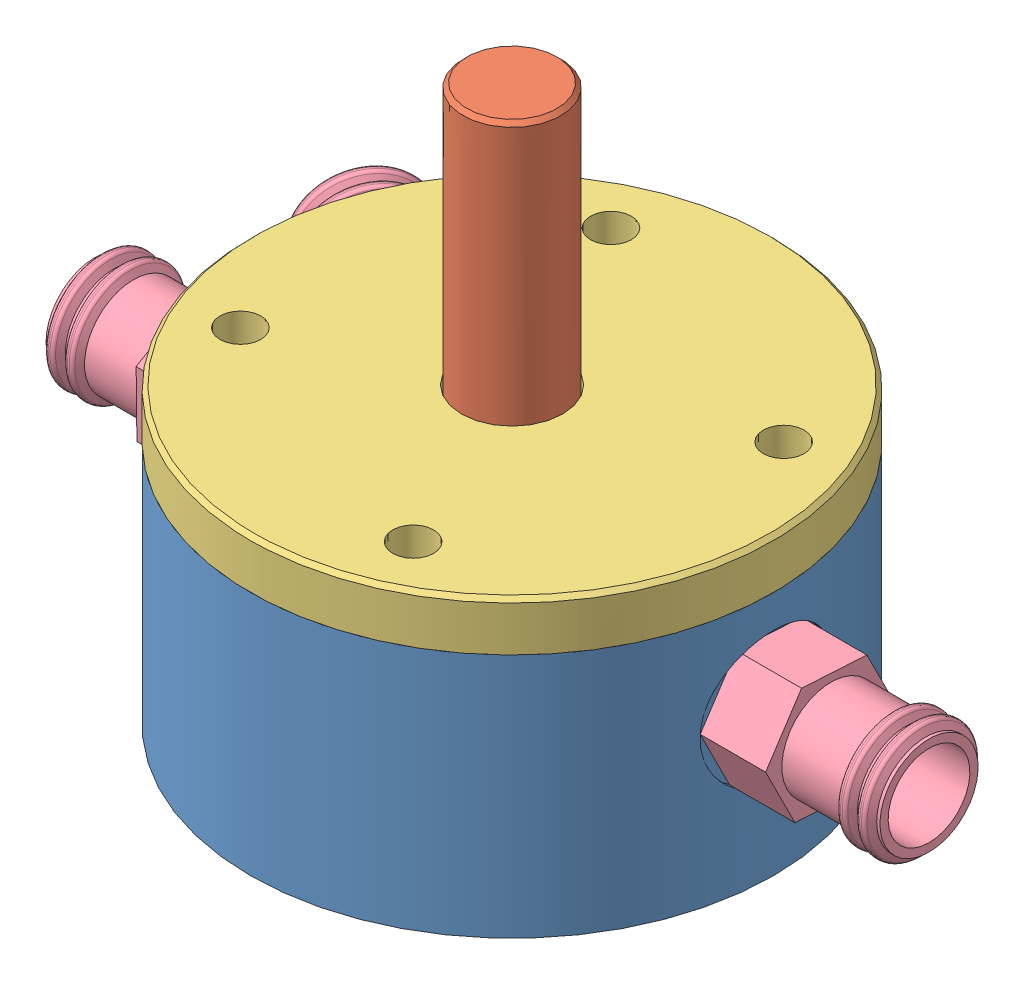
SolidWorks assembly Montagem_Shutter_v10, configuration Default. Lengths in mm.
Overall size (51 34.5 32.14).
6 component instances, 4 part files, 12 mates.
Components (placement in the parent):
- Sede_Inferior_v10-1: Sede_Inferior_v10 [Valor predeterminado<Como usinado>] at origin size (32 15 32)
- Desviador_v10-1: Desviador_v10 [Valor predeterminado] x (-0.941666 0 -0.336549) z (0.336549 0 -0.941666) size (18 34.5 18)
- Sede_superior_v9-1: Sede_superior_v9 [Valor predeterminado] at (0 7.5 0) size (32 4 32)
- Conexao reta-1: Conexao reta [Valor predeterminado] at (17 0 0) x (-1 0 0) z (0 -0.835237 0.54989) size (16 7 8)
- Conexao reta-3: Conexao reta [Valor predeterminado] at (-14.7224 0 -8.5) x (0.866025 0 0.5) z (0.055025 0.993926 -0.095307) size (16 7 8)
- Conexao reta-5: Conexao reta [Valor predeterminado] at (-17 0 0) x (1 0 0) z (0 0.999933 0.011568) size (16 7 8)
Mates (geometry in assembly coordinates):
- Coincident1: coordinate: point of Sede_Inferior_v10-1; point of assembly
- Concentric1: concentric aligned: cylinder of Sede_Inferior_v10-1 through (0 -9 0) axis (0 -1 0) radius 3; cylinder of Desviador_v10-1 through (0 0 0) axis (0 -1 0) radius 3
- Coincident2: coincident anti-aligned: plane of Sede_Inferior_v10-1 through (9 -5 0) normal (0 1 0); plane of Desviador_v10-1 through (-2.825 -5 -1.0096) normal (0 -1 0)
- Concêntrico1: concentric aligned: cylinder of Desviador_v10-1 through (0 0 0) axis (0 -1 0) radius 3; cylinder of Sede_superior_v9-1 through (0 7.5 0) axis (0 -1 0) radius 3.1
- Coincidente3: coincident anti-aligned: plane of Sede_superior_v9-1 through (9 6 0) normal (0 -1 0); plane of Sede_Inferior_v10-1 through (0 6 0) normal (0 1 0)
- Concêntrico4: concentric aligned: cylinder of Sede_Inferior_v10-1 through (5.2827 6 11.3288) axis (0 1 0) radius 1.25; cylinder of Sede_superior_v9-1 through (5.2827 9 11.3288) axis (0 1 0) radius 1.25
- Concêntrico5: concentric anti-aligned: cylinder of Sede_Inferior_v10-1 through (16 0 0) axis (1 0 0) radius 2.25; cylinder of Conexao reta-5 through (-46.7219 0 0) axis (-1 0 0) radius 2.25
- Concêntrico6: concentric aligned: cylinder of Sede_Inferior_v10-1 through (-13.8564 0 -8) axis (-0.866025 0 -0.5) radius 2.25; cylinder of Conexao reta-3 through (-40.4624 0 -23.361) axis (-0.866025 0 -0.5) radius 2.25
- Concêntrico7: concentric anti-aligned: cylinder of Sede_Inferior_v10-1 through (-16 0 0) axis (-1 0 0) radius 2.25; cylinder of Conexao reta-1 through (46.7219 0 0) axis (1 0 0) radius 2.25
- Coincidente4: coincident anti-aligned: plane of Sede_Inferior_v10-1 through (-13.4234 0 -7.75) normal (-0.866025 0 -0.5); plane of Conexao reta-3 through (-11.4355 -0.4402 -11.1931) normal (0.866025 0 0.5)
- Coincidente5: coincident anti-aligned: plane of Sede_Inferior_v10-1 through (-15.5 0 0) normal (-1 0 0); plane of Conexao reta-5 through (-15.5 0.0463 -3.9997) normal (1 0 0)
- Coincidente6: coincident anti-aligned: plane of Sede_Inferior_v10-1 through (15.5 0 0) normal (1 0 0); plane of Conexao reta-1 through (15.5 -2.1996 -3.3409) normal (-1 0 0)
